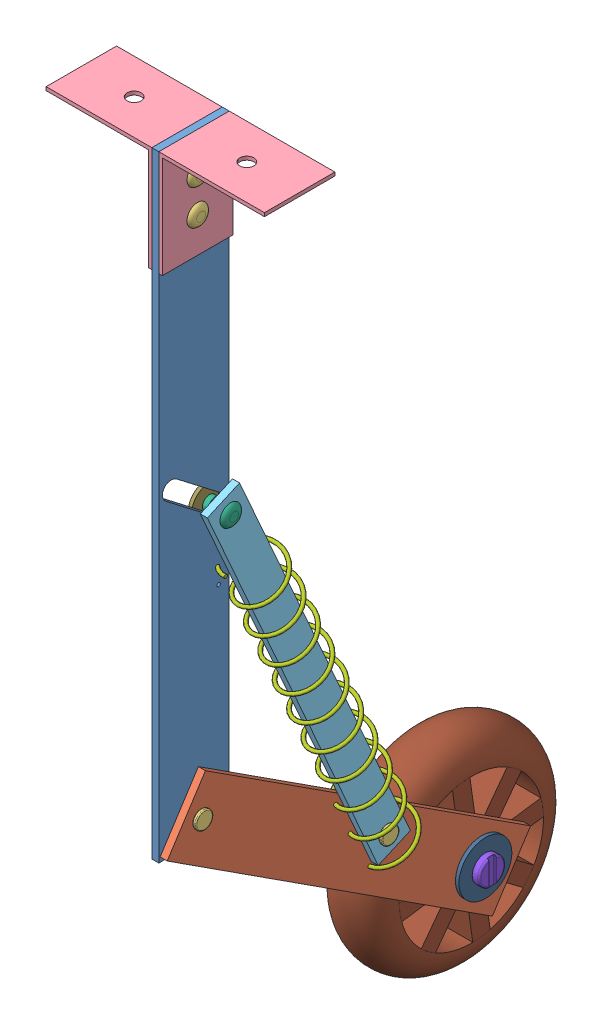
SolidWorks assembly Nose gear, configuration Default. Lengths in mm.
Overall size (62 252.42 122.59).
17 component instances, 12 part files, 35 mates.
Components (placement in the parent):
- Vertical component-1: Vertical component [Default] at (-31.1524 -100.1689 34.5181) size (2 175 20)
- Slant component-1: Slant component [Default] at (-29.1524 -158.5949 -58.2131) x (1 0 0) z (0 -0.839643 0.543138) size (2 110 20)
- Fillet-1: Fillet [Default] at (-31.1524 -93.1689 24.5181) x (0 0.66508 -0.746772) z (0 0.746772 0.66508) size (6 6 6)
- Fuselage attachment-1: Fuselage attachment [Default] at (-29.1524 44.8311 34.5181) size (30 30 20)
- Fuselage attachment-2: Fuselage attachment [Default] at (-31.1524 44.8311 14.5181) x (-1 0 0) z (0 0 -1) size (30 30 20)
- Fillet-2: Fillet [Default] at (-28.1524 64.8311 24.5181) x (0 -0.871668 0.490096) z (0 0.490096 0.871668) size (6 6 6)
- Fillet-3: Fillet [Default] at (-28.1524 54.8311 24.5181) x (0 -0.117224 -0.993105) z (0 -0.993105 0.117224) size (6 6 6)
- End of travel - EOT rod-1: End of travel - EOT rod [Default] at (-27.1524 -127.9074 -23.8031) x (1 0 0) z (0 -0.404439 0.914565) size (2 120 10)
- Fillet-4: Fillet [Default] at (-29.1524 -121.3124 -26.3538) x (0 0.796971 -0.604018) z (0 0.604018 0.796971) size (6 6 6)
- Rivet 2-2: Rivet 2 [Default] at (-25.1524 -20.7102 18.1345) x (0 0.920891 0.38982) z (0 0.38982 -0.920891) size (6 10 6)
- Part8^Nose gear-1: Part8^Nose gear [Default] at origin size (15.37 95.27 53.12) (virtual)
- Bolt-1: Bolt [Default] at (-50.1524 -144.767 -55.248) x (0 0 -1) z (1 0 0) size (7.5 7.5 26.03)
- Nut-1: Nut [Default] at (-49.1524 -144.767 -55.248) x (1 0 0) z (0 -0.314496 -0.949259) size (2 7.5 7.5)
- Tire washer-1: Tire washer [Default] at (-27.1524 -144.767 -55.248) size (1 15 15)
- Tire-1: Tire [Default] at (-30.1524 -144.767 -55.248) x (0 0.989877 0.141929) z (0 -0.141929 0.989877) size (58 17 58)
- Tire washer-2: Tire washer [Default] at (-30.1524 -144.767 -55.248) size (1 15 15)
- E.O.T. washer-1: E.O.T. washer [Default] at (-32.1524 -20.7102 18.1345) x (0 0 -1) z (1 0 0) size (10 10 1)
Mates (geometry in assembly coordinates):
- Concentric1: concentric aligned: cylinder of Vertical component-1 through (-31.1524 -93.1689 24.5181) axis (1 0 0) radius 2; cylinder of Slant component-1 through (-29.1524 -93.1689 24.5181) axis (1 0 0) radius 2
- Concentric2: concentric anti-aligned: cylinder of Vertical component-1 through (-31.1524 -93.1689 24.5181) axis (1 0 0) radius 2; cylinder of Fillet-1 through (-27.1524 -93.1689 24.5181) axis (-1 0 0) radius 2
- Coincident1: coincident anti-aligned: plane of Vertical component-1 through (-29.1524 -100.1689 34.5181) normal (1 0 0); plane of Slant component-1 through (-29.1524 -158.5949 -58.2131) normal (-1 0 0)
- Coincident2: coincident anti-aligned: plane of Vertical component-1 through (-31.1524 -100.1689 34.5181) normal (-1 0 0); plane of Fillet-1 through (-31.1524 -93.1689 24.5181) normal (1 0 0)
- Coincident8: coincident anti-aligned: plane of Vertical component-1 through (-29.1524 -100.1689 34.5181) normal (1 0 0); plane of Fuselage attachment-1 through (-29.1524 44.8311 34.5181) normal (-1 0 0)
- Concentric4: concentric anti-aligned: cylinder of Vertical component-1 through (-31.1524 54.8311 24.5181) axis (1 0 0) radius 2; cylinder of Fuselage attachment-1 through (-28.1524 54.8311 24.5181) axis (-1 0 0) radius 2
- Coincident13: coincident anti-aligned: plane of Vertical component-1 through (-31.1524 -100.1689 34.5181) normal (-1 0 0); plane of Fuselage attachment-2 through (-31.1524 44.8311 14.5181) normal (1 0 0)
- Coincident14: coincident anti-aligned: circle of Vertical component-1; circle of Fuselage attachment-2
- Coincident15: coincident anti-aligned: circle of Vertical component-1; circle of Fuselage attachment-2
- Concentric6: concentric anti-aligned: cylinder of Fuselage attachment-1 through (-28.1524 64.8311 24.5181) axis (-1 0 0) radius 2; cylinder of Fillet-2 through (-32.1524 64.8311 24.5181) axis (1 0 0) radius 2
- Concentric7: concentric anti-aligned: cylinder of Fuselage attachment-1 through (-28.1524 54.8311 24.5181) axis (-1 0 0) radius 2; cylinder of Fillet-3 through (-32.1524 54.8311 24.5181) axis (1 0 0) radius 2
- Coincident16: coincident anti-aligned: plane of Fuselage attachment-1 through (-28.1524 44.8311 34.5181) normal (1 0 0); plane of Fillet-2 through (-28.1524 64.8311 24.5181) normal (-1 0 0)
- Coincident23: coincident aligned: circle of Vertical component-1; cylinder of Fillet-2 through (-32.1524 64.8311 24.5181) axis (1 0 0) radius 2
- Coincident24: coincident anti-aligned: plane of Fuselage attachment-1 through (-28.1524 44.8311 34.5181) normal (1 0 0); plane of Fillet-3 through (-28.1524 54.8311 24.5181) normal (-1 0 0)
- Concentric8: concentric anti-aligned: cylinder of Slant component-1 through (-29.1524 -121.3124 -26.3538) axis (1 0 0) radius 2; cylinder of End of travel - EOT rod-1 through (-25.1524 -121.3124 -26.3538) axis (-1 0 0) radius 2
- Coincident25: coincident aligned: circle of Slant component-1; circle of End of travel - EOT rod-1
- Coincident26: coincident anti-aligned: circle of End of travel - EOT rod-1; cylinder of Fillet-4 through (-25.1524 -121.3124 -26.3538) axis (-1 0 0) radius 2
- Coincident27: coincident anti-aligned: plane of Slant component-1 through (-29.1524 -158.5949 -58.2131) normal (-1 0 0); plane of Fillet-4 through (-29.1524 -121.3124 -26.3538) normal (1 0 0)
- Concentric12: concentric anti-aligned: cylinder of End of travel - EOT rod-1 through (-25.1524 -20.7102 18.1345) axis (-1 0 0) radius 2; cylinder of Rivet 2-2 through (-27.1524 -20.7102 18.1345) axis (1 0 0) radius 2
- Tangent9: tangent anti-aligned: plane of Vertical component-1 through (-31.1524 -22.1505 19.5424) normal (0 0.792624 -0.609711); cylinder of Rivet 2-2 through (-32.1524 -20.7102 18.1345) axis (1 0 0) radius 2
- Coincident38: coincident anti-aligned: plane of End of travel - EOT rod-1 through (-25.1524 -127.9074 -23.8031) normal (1 0 0); plane of Rivet 2-2 through (-25.1524 -20.7102 18.1345) normal (-1 0 0)
- Parallel5: parallel aligned: cylinder of Vertical component-1 through (-31.1524 -20.1689 18.0181) axis (1 0 0) radius 2.5; cylinder of Rivet 2-2 through (-32.1524 -20.7102 18.1345) axis (1 0 0) radius 2
- Lock3: lock: unknown of End of travel - EOT rod-1; unknown of Part8^Nose gear-1
- Concentric15: concentric anti-aligned: cylinder of Slant component-1 through (-29.1524 -144.767 -55.248) axis (1 0 0) radius 2.5; cylinder of Bolt-1 through (-26.1524 -144.767 -55.248) axis (-1 0 0) radius 2.5
- Concentric16: concentric anti-aligned: cylinder of Slant component-1 through (-29.1524 -144.767 -55.248) axis (1 0 0) radius 2.5; cylinder of Tire washer-1 through (-26.1524 -144.767 -55.248) axis (-1 0 0) radius 2.5
- Coincident39: coincident anti-aligned: plane of Slant component-1 through (-27.1524 -158.5949 -58.2131) normal (1 0 0); plane of Tire washer-1 through (-27.1524 -144.767 -55.248) normal (-1 0 0)
- Coincident40: coincident anti-aligned: plane of Bolt-1 through (-26.1524 -144.767 -55.248) normal (-1 0 0); plane of Tire washer-1 through (-26.1524 -144.767 -55.248) normal (1 0 0)
- Concentric17: concentric anti-aligned: circle of Slant component-1; cylinder of Tire washer-2 through (-29.1524 -144.767 -55.248) axis (-1 0 0) radius 2.5
- Coincident42: coincident anti-aligned: plane of Slant component-1 through (-29.1524 -158.5949 -58.2131) normal (-1 0 0); plane of Tire washer-2 through (-29.1524 -144.767 -55.248) normal (1 0 0)
- Concentric18: concentric anti-aligned: circle of Bolt-1; cylinder of Tire-1 through (-30.1524 -144.767 -55.248) axis (-1 0 0) radius 2.5
- Coincident44: coincident anti-aligned: plane of Tire-1 through (-30.1524 -144.767 -55.248) normal (1 0 0); plane of Tire washer-2 through (-30.1524 -144.767 -55.248) normal (-1 0 0)
- Concentric19: concentric anti-aligned: circle of Nut-1; circle of Tire-1
- Coincident47: coincident anti-aligned: plane of Nut-1 through (-47.1524 -144.767 -55.248) normal (1 0 0); plane of Tire-1 through (-47.1524 -144.767 -55.248) normal (-1 0 0)
- Concentric20: concentric anti-aligned: cylinder of Rivet 2-2 through (-32.1524 -20.7102 18.1345) axis (1 0 0) radius 2; cylinder of E.O.T. washer-1 through (-31.1524 -20.7102 18.1345) axis (-1 0 0) radius 2
- Coincident48: coincident anti-aligned: plane of Vertical component-1 through (-31.1524 -100.1689 34.5181) normal (-1 0 0); plane of E.O.T. washer-1 through (-31.1524 -20.7102 18.1345) normal (1 0 0)
